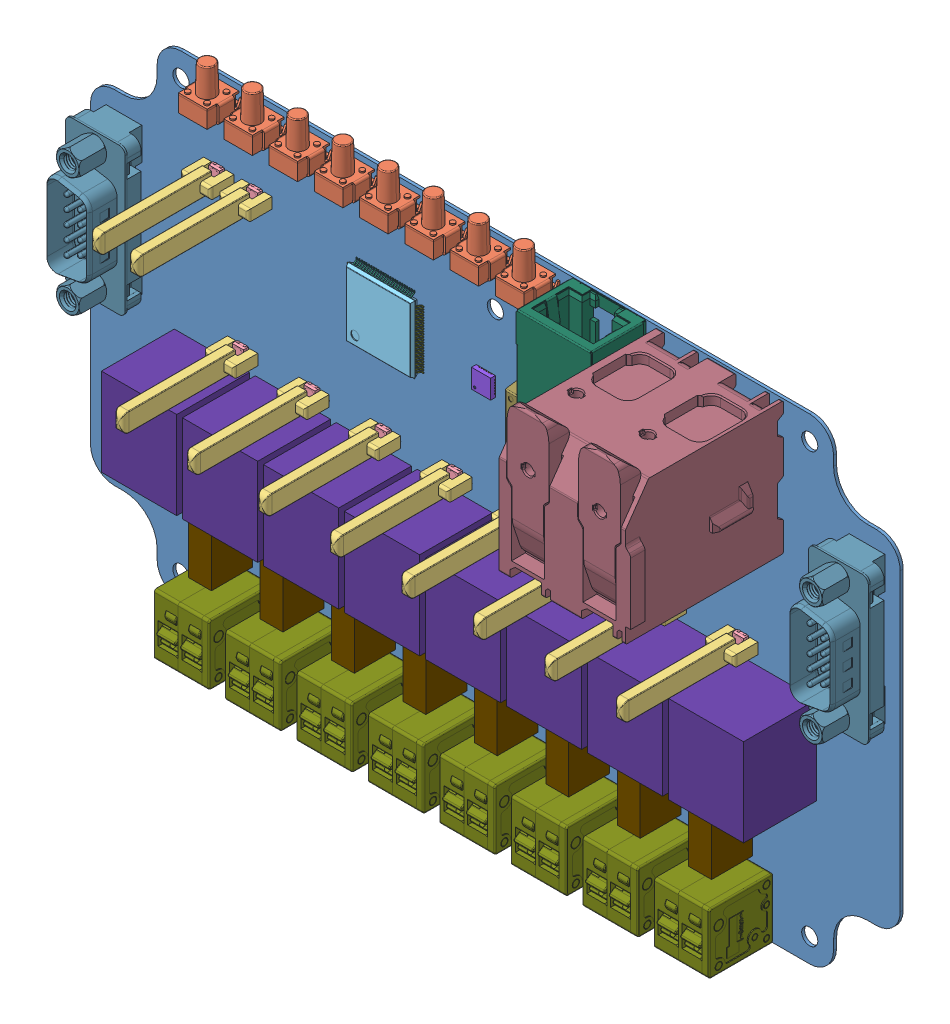
SolidWorks assembly KR-Df-01-EL-00 PCBA 2024_01_15, configuration Default. Lengths in mm.
Overall size (170 104.9 36.71).
192 component instances, 18 part files, 0 mates.
Components (placement in the parent):
- KR-Df-01-EL-00 PCBA 2024_01_15.step-1: KR-Df-01-EL-00 PCBA 2024_01_15.step [Default] at origin size (170 104.9 36.71)
  - Board.step-1: Board.step [Default] at origin size (170 100 0.62)
    - Open CASCADE STEP translator 7.5 1.1.1.step-1: Open CASCADE STEP translator 7.5 1.1.1.step [Default] at (0 0 -0.6237) size (170 100 0.62)
  - S607.step-1: S607.step [Default] at origin size (8.41 12.37 10.52)
    - 1-1825027-1.step-1: 1-1825027-1.step [Default] at (95 95.3 0) x (-1 0 0) z (0 1 0) size (8.41 10.52 12.37)
  - S606.step-1: S606.step [Default] at origin size (8.41 12.37 10.52)
    - 1-1825027-1.step-1: 1-1825027-1.step [Default] at (85.5 95.3 0) x (-1 0 0) z (0 1 0) size (8.41 10.52 12.37)
  - S605.step-1: S605.step [Default] at origin size (8.41 12.37 10.52)
    - 1-1825027-1.step-1: 1-1825027-1.step [Default] at (76 95.3 0) x (-1 0 0) z (0 1 0) size (8.41 10.52 12.37)
  - S604.step-1: S604.step [Default] at origin size (8.41 12.37 10.52)
    - 1-1825027-1.step-1: 1-1825027-1.step [Default] at (66.5 95.3 0) x (-1 0 0) z (0 1 0) size (8.41 10.52 12.37)
  - S603.step-1: S603.step [Default] at origin size (8.41 12.37 10.52)
    - 1-1825027-1.step-1: 1-1825027-1.step [Default] at (57 95.3 0) x (-1 0 0) z (0 1 0) size (8.41 10.52 12.37)
  - S602.step-1: S602.step [Default] at origin size (8.41 12.37 10.52)
    - 1-1825027-1.step-1: 1-1825027-1.step [Default] at (47.5 95.3 0) x (-1 0 0) z (0 1 0) size (8.41 10.52 12.37)
  - S601.step-1: S601.step [Default] at origin size (8.41 12.37 10.52)
    - 1-1825027-1.step-1: 1-1825027-1.step [Default] at (38 95.3 0) x (-1 0 0) z (0 1 0) size (8.41 10.52 12.37)
  - S600.step-1: S600.step [Default] at origin size (8.41 12.37 10.52)
    - 1-1825027-1.step-1: 1-1825027-1.step [Default] at (28.5 95.3 0) x (-1 0 0) z (0 1 0) size (8.41 10.52 12.37)
  - ME609.step-1: ME609.step [Default] at origin size (6.36 3.96 28.65)
    - BIVAR__INC_VLPR-24-1028-2_RGB8421504.step-1: BIVAR__INC_VLPR-24-1028-2_RGB8421504.step [Default] at (27 82 19.1) x (0 1 0) z (1 0 0) size (3.96 28.65 6.35)
  - ME608.step-1: ME608.step [Default] at origin size (6.36 3.96 28.65)
    - BIVAR__INC_VLPR-24-1028-2_RGB8421504.step-1: BIVAR__INC_VLPR-24-1028-2_RGB8421504.step [Default] at (35 82 19.1) x (0 1 0) z (1 0 0) size (3.96 28.65 6.35)
  - ME607.step-1: ME607.step [Default] at origin size (6.36 3.96 28.65)
    - BIVAR__INC_VLPR-24-1028-2_RGB8421504.step-1: BIVAR__INC_VLPR-24-1028-2_RGB8421504.step [Default] at (137 52 19.1) x (0 1 0) z (1 0 0) size (3.96 28.65 6.35)
  - ME606.step-1: ME606.step [Default] at origin size (6.36 3.96 28.65)
    - BIVAR__INC_VLPR-24-1028-2_RGB8421504.step-1: BIVAR__INC_VLPR-24-1028-2_RGB8421504.step [Default] at (122 52 19.1) x (0 1 0) z (1 0 0) size (3.96 28.65 6.35)
  - ME605.step-1: ME605.step [Default] at origin size (6.36 3.96 28.65)
    - BIVAR__INC_VLPR-24-1028-2_RGB8421504.step-1: BIVAR__INC_VLPR-24-1028-2_RGB8421504.step [Default] at (107 52 19.1) x (0 1 0) z (1 0 0) size (3.96 28.65 6.35)
  - ME604.step-1: ME604.step [Default] at origin size (6.36 3.96 28.65)
    - BIVAR__INC_VLPR-24-1028-2_RGB8421504.step-1: BIVAR__INC_VLPR-24-1028-2_RGB8421504.step [Default] at (92 52 19.1) x (0 1 0) z (1 0 0) size (3.96 28.65 6.35)
  - ME603.step-1: ME603.step [Default] at origin size (6.36 3.96 28.65)
    - BIVAR__INC_VLPR-24-1028-2_RGB8421504.step-1: BIVAR__INC_VLPR-24-1028-2_RGB8421504.step [Default] at (77 52 19.1) x (0 1 0) z (1 0 0) size (3.96 28.65 6.35)
  - ME602.step-1: ME602.step [Default] at origin size (6.36 3.96 28.65)
    - BIVAR__INC_VLPR-24-1028-2_RGB8421504.step-1: BIVAR__INC_VLPR-24-1028-2_RGB8421504.step [Default] at (62 52 19.1) x (0 1 0) z (1 0 0) size (3.96 28.65 6.35)
  - ME601.step-1: ME601.step [Default] at origin size (6.36 3.96 28.65)
    - BIVAR__INC_VLPR-24-1028-2_RGB8421504.step-1: BIVAR__INC_VLPR-24-1028-2_RGB8421504.step [Default] at (47 52 19.1) x (0 1 0) z (1 0 0) size (3.96 28.65 6.35)
  - ME600.step-1: ME600.step [Default] at origin size (6.36 3.96 28.65)
    - BIVAR__INC_VLPR-24-1028-2_RGB8421504.step-1: BIVAR__INC_VLPR-24-1028-2_RGB8421504.step [Default] at (32 52 19.1) x (0 1 0) z (1 0 0) size (3.96 28.65 6.35)
  - D609.step-1: D609.step [Default] at origin size (2.4 2.7 1.1)
    - IN-PI22TAT.step-1: IN-PI22TAT.step [Default] at (27 82 0) x (0 1 0) z (1 0 0) size (2.7 1.1 2.4)
  - D608.step-1: D608.step [Default] at origin size (2.4 2.7 1.1)
    - IN-PI22TAT.step-1: IN-PI22TAT.step [Default] at (35 82 0) x (0 1 0) z (1 0 0) size (2.7 1.1 2.4)
  - D607.step-1: D607.step [Default] at origin size (2.4 2.7 1.1)
    - IN-PI22TAT.step-1: IN-PI22TAT.step [Default] at (137 52 0) x (0 -1 0) z (-1 0 0) size (2.7 1.1 2.4)
  - D606.step-1: D606.step [Default] at origin size (2.4 2.7 1.1)
    - IN-PI22TAT.step-1: IN-PI22TAT.step [Default] at (122 52 0) x (0 -1 0) z (-1 0 0) size (2.7 1.1 2.4)
  - D605.step-1: D605.step [Default] at origin size (2.4 2.7 1.1)
    - IN-PI22TAT.step-1: IN-PI22TAT.step [Default] at (107 52 0) x (0 -1 0) z (-1 0 0) size (2.7 1.1 2.4)
  - D604.step-1: D604.step [Default] at origin size (2.4 2.7 1.1)
    - IN-PI22TAT.step-1: IN-PI22TAT.step [Default] at (92 52 0) x (0 -1 0) z (-1 0 0) size (2.7 1.1 2.4)
  - D603.step-1: D603.step [Default] at origin size (2.4 2.7 1.1)
    - IN-PI22TAT.step-1: IN-PI22TAT.step [Default] at (77 52 0) x (0 -1 0) z (-1 0 0) size (2.7 1.1 2.4)
  - D602.step-1: D602.step [Default] at origin size (2.4 2.7 1.1)
    - IN-PI22TAT.step-1: IN-PI22TAT.step [Default] at (62 52 0) x (0 -1 0) z (-1 0 0) size (2.7 1.1 2.4)
  - D601.step-1: D601.step [Default] at origin size (2.4 2.7 1.1)
    - IN-PI22TAT.step-1: IN-PI22TAT.step [Default] at (47 52 0) x (0 -1 0) z (-1 0 0) size (2.7 1.1 2.4)
  - D600.step-1: D600.step [Default] at origin size (2.4 2.7 1.1)
    - IN-PI22TAT.step-1: IN-PI22TAT.step [Default] at (32 52 0) x (0 -1 0) z (-1 0 0) size (2.7 1.1 2.4)
  - U500.step-1: U500.step [Default] at origin size (16 16 1.6)
    - STM32H573VIT6_RGB8421504.step-1: STM32H573VIT6_RGB8421504.step [Default] at (62 73 0) x (0 1 0) z (0 0 1) size (16 16 1.6)
      - Body.step-1: Body.step [Default] at origin size (14 14 1.5)
      - PinsArrayLR.step-1: PinsArrayLR.step [Default] at origin size (16 12.22 0.86)
      - PinsArrayTB.step-1: PinsArrayTB.step [Default] at origin size (12.22 16 0.86)
  - U200.step-1: U200.step [Default] at origin size (4 4 1)
    - 6084536176.step-1: 6084536176.step [Default] at (83 72 0) x (0 1 0) z (0 0 1) size (4 4 1)
      - Body-0.step-1: Body-0.step [Default] at (-2 -2 0) size (4 4 1)
        - Open CASCADE STEP translator 6.8 14.2.1.step-1: Open CASCADE STEP translator 6.8 14.2.1.step [Default] at origin size (4 4 1)
      - Pin_Shape.step-1: Pin_Shape.step [Default] at (-2 -1.37 0) size (0.4 0.24 0.2)
        - Open CASCADE STEP translator 6.8 14.4.1.step-1: Open CASCADE STEP translator 6.8 14.4.1.step [Default] at origin size (0.4 0.24 0.2)
      - Pin_Shape.step-2: Pin_Shape.step [Default] at (2 1.37 0) x (-1 0 0) z (0 0 1) size (0.4 0.24 0.2)
        - Open CASCADE STEP translator 6.8 14.4.1.step-1: Open CASCADE STEP translator 6.8 14.4.1.step [Default] at origin size (0.4 0.24 0.2)
      - Pin_Shape.step-3: Pin_Shape.step [Default] at (-2 -0.87 0) size (0.4 0.24 0.2)
        - Open CASCADE STEP translator 6.8 14.4.1.step-1: Open CASCADE STEP translator 6.8 14.4.1.step [Default] at origin size (0.4 0.24 0.2)
      - Pin_Shape.step-4: Pin_Shape.step [Default] at (2 0.87 0) x (-1 0 0) z (0 0 1) size (0.4 0.24 0.2)
        - Open CASCADE STEP translator 6.8 14.4.1.step-1: Open CASCADE STEP translator 6.8 14.4.1.step [Default] at origin size (0.4 0.24 0.2)
      - Pin_Shape.step-5: Pin_Shape.step [Default] at (-2 -0.37 0) size (0.4 0.24 0.2)
        - Open CASCADE STEP translator 6.8 14.4.1.step-1: Open CASCADE STEP translator 6.8 14.4.1.step [Default] at origin size (0.4 0.24 0.2)
      - Pin_Shape.step-6: Pin_Shape.step [Default] at (2 0.37 0) x (-1 0 0) z (0 0 1) size (0.4 0.24 0.2)
        - Open CASCADE STEP translator 6.8 14.4.1.step-1: Open CASCADE STEP translator 6.8 14.4.1.step [Default] at origin size (0.4 0.24 0.2)
      - Pin_Shape.step-7: Pin_Shape.step [Default] at (-2 0.13 0) size (0.4 0.24 0.2)
        - Open CASCADE STEP translator 6.8 14.4.1.step-1: Open CASCADE STEP translator 6.8 14.4.1.step [Default] at origin size (0.4 0.24 0.2)
      - Pin_Shape.step-8: Pin_Shape.step [Default] at (2 -0.13 0) x (-1 0 0) z (0 0 1) size (0.4 0.24 0.2)
        - Open CASCADE STEP translator 6.8 14.4.1.step-1: Open CASCADE STEP translator 6.8 14.4.1.step [Default] at origin size (0.4 0.24 0.2)
      - Pin_Shape.step-9: Pin_Shape.step [Default] at (-2 0.63 0) size (0.4 0.24 0.2)
        - Open CASCADE STEP translator 6.8 14.4.1.step-1: Open CASCADE STEP translator 6.8 14.4.1.step [Default] at origin size (0.4 0.24 0.2)
      - Pin_Shape.step-10: Pin_Shape.step [Default] at (2 -0.63 0) x (-1 0 0) z (0 0 1) size (0.4 0.24 0.2)
        - Open CASCADE STEP translator 6.8 14.4.1.step-1: Open CASCADE STEP translator 6.8 14.4.1.step [Default] at origin size (0.4 0.24 0.2)
      - Pin_Shape.step-11: Pin_Shape.step [Default] at (-2 1.13 0) size (0.4 0.24 0.2)
        - Open CASCADE STEP translator 6.8 14.4.1.step-1: Open CASCADE STEP translator 6.8 14.4.1.step [Default] at origin size (0.4 0.24 0.2)
      - Pin_Shape.step-12: Pin_Shape.step [Default] at (2 -1.13 0) x (-1 0 0) z (0 0 1) size (0.4 0.24 0.2)
        - Open CASCADE STEP translator 6.8 14.4.1.step-1: Open CASCADE STEP translator 6.8 14.4.1.step [Default] at origin size (0.4 0.24 0.2)
      - Pin_Shape.step-13: Pin_Shape.step [Default] at (-1.13 -2 0) x (0 1 0) z (0 0 1) size (0.4 0.24 0.2)
        - Open CASCADE STEP translator 6.8 14.4.1.step-1: Open CASCADE STEP translator 6.8 14.4.1.step [Default] at origin size (0.4 0.24 0.2)
      - Pin_Shape.step-14: Pin_Shape.step [Default] at (1.13 2 0) x (0 -1 0) z (0 0 1) size (0.4 0.24 0.2)
        - Open CASCADE STEP translator 6.8 14.4.1.step-1: Open CASCADE STEP translator 6.8 14.4.1.step [Default] at origin size (0.4 0.24 0.2)
      - Pin_Shape.step-15: Pin_Shape.step [Default] at (-0.63 -2 0) x (0 1 0) z (0 0 1) size (0.4 0.24 0.2)
        - Open CASCADE STEP translator 6.8 14.4.1.step-1: Open CASCADE STEP translator 6.8 14.4.1.step [Default] at origin size (0.4 0.24 0.2)
      - Pin_Shape.step-16: Pin_Shape.step [Default] at (0.63 2 0) x (0 -1 0) z (0 0 1) size (0.4 0.24 0.2)
        - Open CASCADE STEP translator 6.8 14.4.1.step-1: Open CASCADE STEP translator 6.8 14.4.1.step [Default] at origin size (0.4 0.24 0.2)
      - Pin_Shape.step-17: Pin_Shape.step [Default] at (-0.13 -2 0) x (0 1 0) z (0 0 1) size (0.4 0.24 0.2)
        - Open CASCADE STEP translator 6.8 14.4.1.step-1: Open CASCADE STEP translator 6.8 14.4.1.step [Default] at origin size (0.4 0.24 0.2)
      - Pin_Shape.step-18: Pin_Shape.step [Default] at (0.13 2 0) x (0 -1 0) z (0 0 1) size (0.4 0.24 0.2)
        - Open CASCADE STEP translator 6.8 14.4.1.step-1: Open CASCADE STEP translator 6.8 14.4.1.step [Default] at origin size (0.4 0.24 0.2)
      - Pin_Shape.step-19: Pin_Shape.step [Default] at (0.37 -2 0) x (0 1 0) z (0 0 1) size (0.4 0.24 0.2)
        - Open CASCADE STEP translator 6.8 14.4.1.step-1: Open CASCADE STEP translator 6.8 14.4.1.step [Default] at origin size (0.4 0.24 0.2)
      - Pin_Shape.step-20: Pin_Shape.step [Default] at (-0.37 2 0) x (0 -1 0) z (0 0 1) size (0.4 0.24 0.2)
        - Open CASCADE STEP translator 6.8 14.4.1.step-1: Open CASCADE STEP translator 6.8 14.4.1.step [Default] at origin size (0.4 0.24 0.2)
      - Pin_Shape.step-21: Pin_Shape.step [Default] at (0.87 -2 0) x (0 1 0) z (0 0 1) size (0.4 0.24 0.2)
        - Open CASCADE STEP translator 6.8 14.4.1.step-1: Open CASCADE STEP translator 6.8 14.4.1.step [Default] at origin size (0.4 0.24 0.2)
      - Pin_Shape.step-22: Pin_Shape.step [Default] at (-0.87 2 0) x (0 -1 0) z (0 0 1) size (0.4 0.24 0.2)
        - Open CASCADE STEP translator 6.8 14.4.1.step-1: Open CASCADE STEP translator 6.8 14.4.1.step [Default] at origin size (0.4 0.24 0.2)
      - Pin_Shape.step-23: Pin_Shape.step [Default] at (1.37 -2 0) x (0 1 0) z (0 0 1) size (0.4 0.24 0.2)
        - Open CASCADE STEP translator 6.8 14.4.1.step-1: Open CASCADE STEP translator 6.8 14.4.1.step [Default] at origin size (0.4 0.24 0.2)
      - Pin_Shape.step-24: Pin_Shape.step [Default] at (-1.37 2 0) x (0 -1 0) z (0 0 1) size (0.4 0.24 0.2)
        - Open CASCADE STEP translator 6.8 14.4.1.step-1: Open CASCADE STEP translator 6.8 14.4.1.step [Default] at origin size (0.4 0.24 0.2)
      - Open CASCADE STEP translator 6.8 14.1.step-1: Open CASCADE STEP translator 6.8 14.1.step [Default] at (-2 -2 0) size (0.51 0.51 0.01)
      - Thermal_Shape.step-1: Thermal_Shape.step [Default] at (-1.25 -1.25 -0.001) size (2.5 2.5 0)
  - T200.step-1: T200.step [Default] at origin size (9.3 12.8 5.68)
    - PT61018PEL.step-1: PT61018PEL.step [Default] at (99.35 78.3999 5.65) x (0 -1 0) z (1 0 0) size (12.8 5.68 9.3)
  - J400.step-1: J400.step [Default] at origin size (27.81 32.01 33.2)
    - 2616-1352.step-1: 2616-1352.step [Default] at (120.5 89.5 0) x (0 1 0) z (1 0 0) size (32.01 33.2 27.81)
  - J301.step-1: J301.step [Default] at origin size (12.55 30.81 15.4)
    - L717TSEH09POL2RM8--3DModel-STEP-533217.step-1: L717TSEH09POL2RM8--3DModel-STEP-533217.step [Default] at (169.275 51.58 0) x (0 1 0) z (1 0 0) size (30.81 15.4 12.55)
  - J300.step-1: J300.step [Default] at origin size (12.55 30.81 15.4)
    - L717TSEH09POL2RM8--3DModel-STEP-533217.step-1: L717TSEH09POL2RM8--3DModel-STEP-533217.step [Default] at (13.275 51.58 0) x (0 1 0) z (1 0 0) size (30.81 15.4 12.55)
  - P200.step-1: P200.step [Default] at origin size (16.33 18.55 13.95)
    - M-RJLSE-4X381-01T-REVT1.step-1: M-RJLSE-4X381-01T-REVT1.step [Default] at (108.9999 99.725 0) x (1 0 0) z (0 1 0) size (16.33 13.95 18.55)
  - P103.step-1: P103.step [Default] at origin size (11.62 12.71 17.41)
    - DGPS2.5R-5.0-02P-14-00Z(H).step-1: DGPS2.5R-5.0-02P-14-00Z(H).step [Default] at (76.8 0.1 0) x (1 0 0) z (0 -1 0) size (11.62 17.41 12.71)
  - P101.step-1: P101.step [Default] at origin size (11.62 12.71 17.41)
    - DGPS2.5R-5.0-02P-14-00Z(H).step-1: DGPS2.5R-5.0-02P-14-00Z(H).step [Default] at (46.8 0.1 0) x (1 0 0) z (0 -1 0) size (11.62 17.41 12.71)
  - P106.step-1: P106.step [Default] at origin size (11.62 12.71 17.41)
    - DGPS2.5R-5.0-02P-14-00Z(H).step-1: DGPS2.5R-5.0-02P-14-00Z(H).step [Default] at (121.8 0.1 0) x (1 0 0) z (0 -1 0) size (11.62 17.41 12.71)
  - P104.step-1: P104.step [Default] at origin size (11.62 12.71 17.41)
    - DGPS2.5R-5.0-02P-14-00Z(H).step-1: DGPS2.5R-5.0-02P-14-00Z(H).step [Default] at (91.8 0.1 0) x (1 0 0) z (0 -1 0) size (11.62 17.41 12.71)
  - P100.step-1: P100.step [Default] at origin size (11.62 12.71 17.41)
    - DGPS2.5R-5.0-02P-14-00Z(H).step-1: DGPS2.5R-5.0-02P-14-00Z(H).step [Default] at (31.8 0.1 0) x (1 0 0) z (0 -1 0) size (11.62 17.41 12.71)
  - P107.step-1: P107.step [Default] at origin size (11.62 12.71 17.41)
    - DGPS2.5R-5.0-02P-14-00Z(H).step-1: DGPS2.5R-5.0-02P-14-00Z(H).step [Default] at (136.8 0.1 0) x (1 0 0) z (0 -1 0) size (11.62 17.41 12.71)
  - P105.step-1: P105.step [Default] at origin size (11.62 12.71 17.41)
    - DGPS2.5R-5.0-02P-14-00Z(H).step-1: DGPS2.5R-5.0-02P-14-00Z(H).step [Default] at (106.8 0.1 0) x (1 0 0) z (0 -1 0) size (11.62 17.41 12.71)
  - P102.step-1: P102.step [Default] at origin size (11.62 12.71 17.41)
    - DGPS2.5R-5.0-02P-14-00Z(H).step-1: DGPS2.5R-5.0-02P-14-00Z(H).step [Default] at (61.8 0.1 0) x (1 0 0) z (0 -1 0) size (11.62 17.41 12.71)
  - K104.step-1: K104.step [Default] at origin size (15.8 18.4 15.29)
    - 6213569776.step-1: 6213569776.step [Default] at (93.5 39.55 0) size (15.8 18.4 15.29)
      - Extruded.step-1: Extruded.step [Default] at origin size (15.8 18.4 15.29)
  - K101.step-1: K101.step [Default] at origin size (15.8 18.4 15.29)
    - 6213569776.step-1: 6213569776.step [Default] at (42.5 39.55 0) size (15.8 18.4 15.29)
      - Extruded.step-1: Extruded.step [Default] at origin size (15.8 18.4 15.29)
  - K106.step-1: K106.step [Default] at origin size (15.8 18.4 15.29)
    - 6213569776.step-1: 6213569776.step [Default] at (127.5 39.55 0) size (15.8 18.4 15.29)
      - Extruded.step-1: Extruded.step [Default] at origin size (15.8 18.4 15.29)
  - K103.step-1: K103.step [Default] at origin size (15.8 18.4 15.29)
    - 6213569776.step-1: 6213569776.step [Default] at (76.5 39.55 0) size (15.8 18.4 15.29)
      - Extruded.step-1: Extruded.step [Default] at origin size (15.8 18.4 15.29)
  - K100.step-1: K100.step [Default] at origin size (15.8 18.4 15.29)
    - 6213569776.step-1: 6213569776.step [Default] at (25.5 39.55 0) size (15.8 18.4 15.29)
      - Extruded.step-1: Extruded.step [Default] at origin size (15.8 18.4 15.29)
  - K107.step-1: K107.step [Default] at origin size (15.8 18.4 15.29)
    - 6213569776.step-1: 6213569776.step [Default] at (144.5 39.55 0) size (15.8 18.4 15.29)
      - Extruded.step-1: Extruded.step [Default] at origin size (15.8 18.4 15.29)
  - K105.step-1: K105.step [Default] at origin size (15.8 18.4 15.29)
    - 6213569776.step-1: 6213569776.step [Default] at (110.5 39.55 0) size (15.8 18.4 15.29)
      - Extruded.step-1: Extruded.step [Default] at origin size (15.8 18.4 15.29)
  - K102.step-1: K102.step [Default] at origin size (15.8 18.4 15.29)
    - 6213569776.step-1: 6213569776.step [Default] at (59.5 39.55 0) size (15.8 18.4 15.29)
      - Extruded.step-1: Extruded.step [Default] at origin size (15.8 18.4 15.29)
  - F103.step-1: F103.step [Default] at origin size (4.8 14.7 8.6)
    - 6213567456.step-1: 6213567456.step [Default] at (76.6 21 0) size (4.8 14.7 8.6)
      - Extruded-1.step-1: Extruded-1.step [Default] at origin size (4.8 14.7 8.6)
  - F101.step-1: F101.step [Default] at origin size (4.8 14.7 8.6)
    - 6213567456.step-1: 6213567456.step [Default] at (46.6 21 0) size (4.8 14.7 8.6)
      - Extruded-1.step-1: Extruded-1.step [Default] at origin size (4.8 14.7 8.6)
  - F106.step-1: F106.step [Default] at origin size (4.8 14.7 8.6)
    - 6213567456.step-1: 6213567456.step [Default] at (121.6 21 0) size (4.8 14.7 8.6)
      - Extruded-1.step-1: Extruded-1.step [Default] at origin size (4.8 14.7 8.6)
  - F104.step-1: F104.step [Default] at origin size (4.8 14.7 8.6)
    - 6213567456.step-1: 6213567456.step [Default] at (91.6 21 0) size (4.8 14.7 8.6)
      - Extruded-1.step-1: Extruded-1.step [Default] at origin size (4.8 14.7 8.6)
  - F100.step-1: F100.step [Default] at origin size (4.8 14.7 8.6)
    - 6213567456.step-1: 6213567456.step [Default] at (31.6 21 0) size (4.8 14.7 8.6)
      - Extruded-1.step-1: Extruded-1.step [Default] at origin size (4.8 14.7 8.6)
  - F107.step-1: F107.step [Default] at origin size (4.8 14.7 8.6)
    - 6213567456.step-1: 6213567456.step [Default] at (136.6 21 0) size (4.8 14.7 8.6)
      - Extruded-1.step-1: Extruded-1.step [Default] at origin size (4.8 14.7 8.6)
  - F105.step-1: F105.step [Default] at origin size (4.8 14.7 8.6)
    - 6213567456.step-1: 6213567456.step [Default] at (106.6 21 0) size (4.8 14.7 8.6)
      - Extruded-1.step-1: Extruded-1.step [Default] at origin size (4.8 14.7 8.6)
  - F102.step-1: F102.step [Default] at origin size (4.8 14.7 8.6)
    - 6213567456.step-1: 6213567456.step [Default] at (61.6 21 0) size (4.8 14.7 8.6)
      - Extruded-1.step-1: Extruded-1.step [Default] at origin size (4.8 14.7 8.6)
